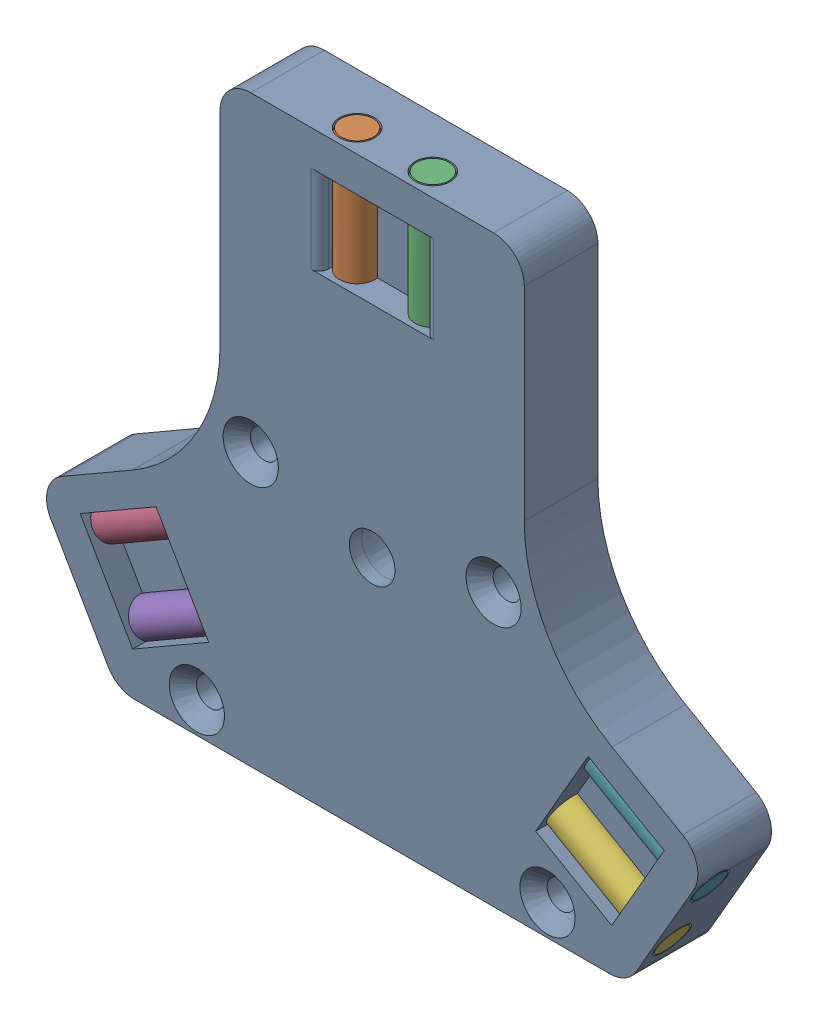
SolidWorks assembly coupling_plate_assembly, configuration Default. Lengths in mm.
Overall size (74.69 66.57 8.62).
7 component instances, 2 part files, 0 mates.
Components (placement in the parent):
- coupling_plate_Carriage Coupler Plate-1: coupling_plate_Carriage Coupler Plate [Default] at (97.5575 375.4795 75.9434) size (74.3 66.57 8.4)
- dowel_pin_4mm_d_20mm_l_91585A457_91585A457-1: dowel_pin_4mm_d_20mm_l_91585A457_91585A457 [Default] at (93.2415 404.4795 75.9434) x (0 1 0) z (0.777637 0 0.628713) size (20 4 4)
- dowel_pin_4mm_d_20mm_l_91585A457_91585A457-2: dowel_pin_4mm_d_20mm_l_91585A457_91585A457 [Default] at (101.8736 404.4795 75.9434) x (0 1 0) z (0.784909 0 0.619611) size (20 4 4)
- dowel_pin_4mm_d_20mm_l_91585A457_91585A457-3: dowel_pin_4mm_d_20mm_l_91585A457_91585A457 [Default] at (70.2848 364.7173 75.9434) x (-0.866025 -0.5 0) z (-0.329564 0.570821 0.752031) size (20 4 4)
- dowel_pin_4mm_d_20mm_l_91585A457_91585A457-4: dowel_pin_4mm_d_20mm_l_91585A457_91585A457 [Default] at (74.6008 357.2417 75.9434) x (-0.866025 -0.5 0) z (-0.329564 0.570821 0.752031) size (20 4 4)
- dowel_pin_4mm_d_20mm_l_91585A457_91585A457-5: dowel_pin_4mm_d_20mm_l_91585A457_91585A457 [Default] at (120.5142 357.2417 75.9434) x (-0.866025 0.5 0) z (0.329564 0.570821 0.752031) size (20 4 4)
- dowel_pin_4mm_d_20mm_l_91585A457_91585A457-6: dowel_pin_4mm_d_20mm_l_91585A457_91585A457 [Default] at (124.8303 364.7173 75.9434) x (-0.866025 0.5 0) z (0.329564 0.570821 0.752031) size (20 4 4)
